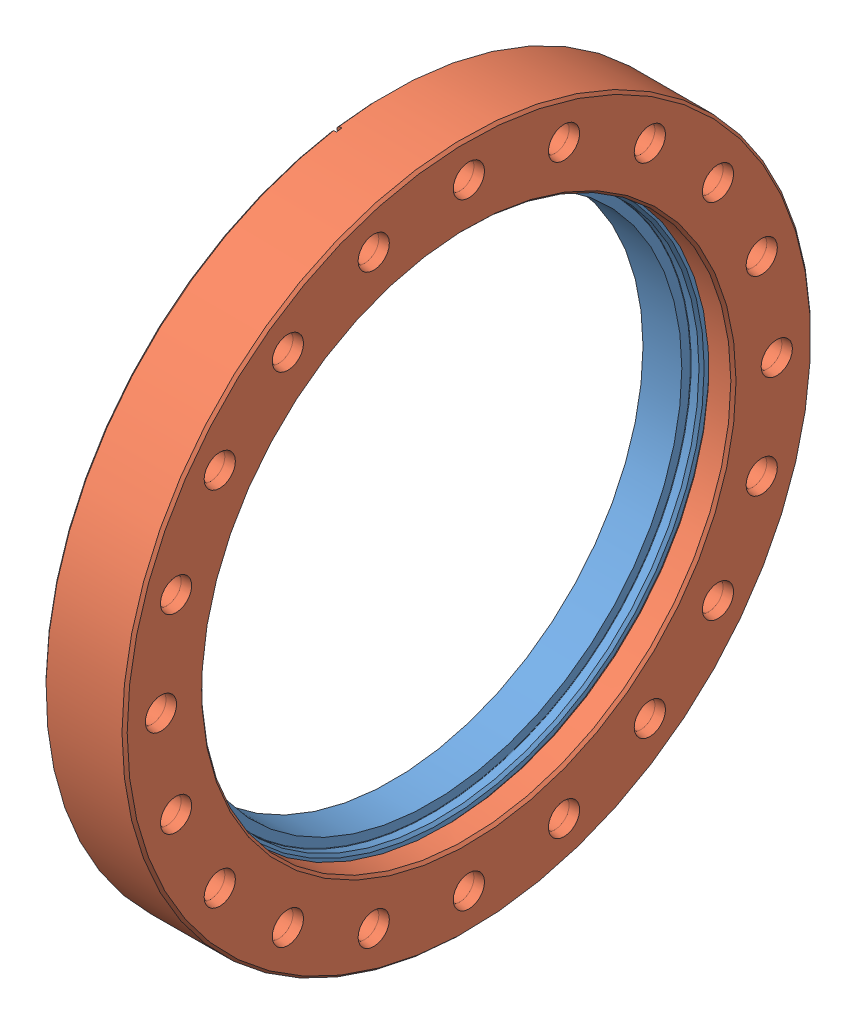
SolidWorks assembly 100031, configuration Default. Lengths in mm.
Overall size (23.88 202.44 202.44).
2 component instances, 2 part files, 3 mates.
Components (placement in the parent):
- 910031-1: 910031 [Default] at (73.7655 101.0261 114.2751) size (15.13 171.22 171.22)
- 915008-1: 915008 [Default] at (73.1051 101.0261 114.2751) size (23.88 202.44 202.44)
Mates (geometry in assembly coordinates):
- Concentric1: concentric aligned: cylinder of 910031-1 through (73.7655 101.0261 114.2751) axis (-1 0 0) radius 85.6107; cylinder of 915008-1 through (73.1051 101.0261 114.2751) axis (-1 0 0) radius 101.219
- Coincident1: coincident anti-aligned: plane of 910031-1 through (88.9547 177.4801 114.2751) normal (1 0 0); plane of 915008-1 through (88.9547 178.2809 77.1205) normal (-1 0 0)
- Parallel1: parallel aligned: plane of 915008-1 through (73.1051 101.0261 114.2751) normal (0 0 1)
